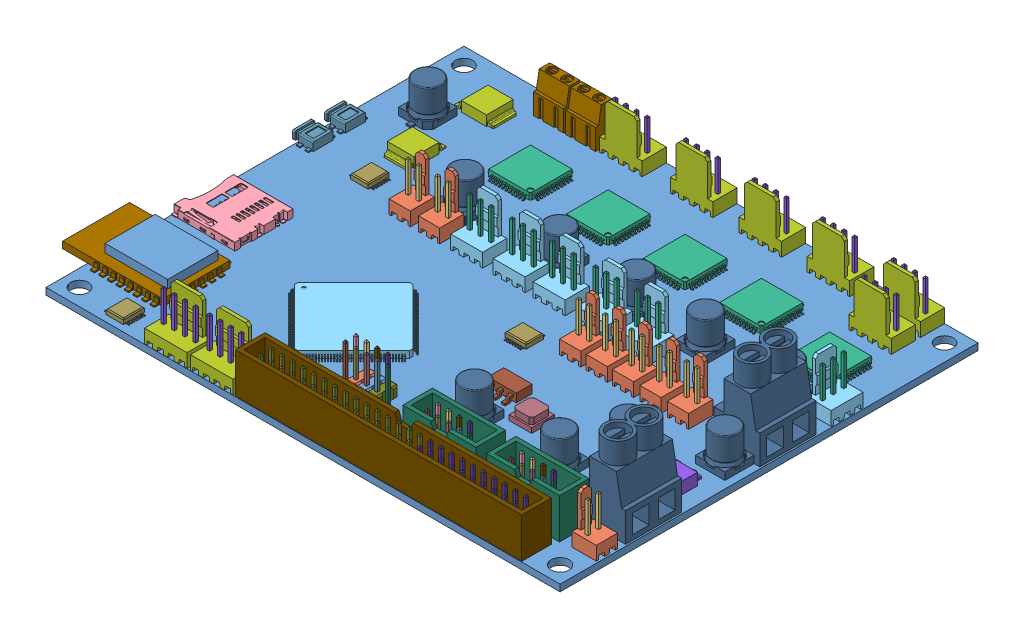
SolidWorks assembly Duet WIfi Rev 4, configuration Predeterminado. Lengths in mm.
Overall size (129 22.52 100).
221 component instances, 40 part files, 0 mates.
Components (placement in the parent):
- Main PCB v56-1: Main PCB v56 [Predeterminado] at origin size (123 1.6 100)
- Molex PCB 2 pin v2-1: Molex PCB 2 pin v2 [Predeterminado] at (-35.5344 13.1082 -6.1109) x (1 0 0) z (0 1 0) size (5.08 5.79 14.92)
  - BASE9710016_1-1: BASE9710016_1 [Predeterminado] at (2.54 2.895 -8.22) size (5.08 5.79 11.5)
  - PINO9710016_1-1: PINO9710016_1 [Predeterminado] at (1.27 3.325 -0.72) size (0.65 0.65 14.2)
  - PINO9710016_1-2: PINO9710016_1 [Predeterminado] at (3.81 3.325 -0.72) size (0.65 0.65 14.2)
- Molex PCB 2 pin v2_1-1: Molex PCB 2 pin v2_1 [Predeterminado] at (-28.4802 13.1082 -6.1109) x (1 0 0) z (0 1 0) size (5.08 5.79 14.92)
  - BASE9710016_1-1: BASE9710016_1 [Predeterminado] at (2.54 2.895 -8.22) size (5.08 5.79 11.5)
  - PINO9710016_1-1: PINO9710016_1 [Predeterminado] at (1.27 3.325 -0.72) size (0.65 0.65 14.2)
  - PINO9710016_1-2: PINO9710016_1 [Predeterminado] at (3.81 3.325 -0.72) size (0.65 0.65 14.2)
- microSD1 v4-1: microSD1 v4 [Predeterminado] at (-62.4462 1.5952 12.9853) x (0 0 1) z (-1 0 0) size (14.1 1.88 15.2)
- Molex PCB 2 pin v2_2-1: Molex PCB 2 pin v2_2 [Predeterminado] at (13.9179 13.1082 2.5426) x (1 0 0) z (0 1 0) size (5.08 5.79 14.92)
  - BASE9710016_1-1: BASE9710016_1 [Predeterminado] at (2.54 2.895 -8.22) size (5.08 5.79 11.5)
  - PINO9710016_1-1: PINO9710016_1 [Predeterminado] at (1.27 3.325 -0.72) size (0.65 0.65 14.2)
  - PINO9710016_1-2: PINO9710016_1 [Predeterminado] at (3.81 3.325 -0.72) size (0.65 0.65 14.2)
- Molex PCB 2 pin v2_3-1: Molex PCB 2 pin v2_3 [Predeterminado] at (20.2886 13.1082 2.5426) x (1 0 0) z (0 1 0) size (5.08 5.79 14.92)
  - BASE9710016_1-1: BASE9710016_1 [Predeterminado] at (2.54 2.895 -8.22) size (5.08 5.79 11.5)
  - PINO9710016_1-1: PINO9710016_1 [Predeterminado] at (1.27 3.325 -0.72) size (0.65 0.65 14.2)
  - PINO9710016_1-2: PINO9710016_1 [Predeterminado] at (3.81 3.325 -0.72) size (0.65 0.65 14.2)
- Molex PCB 2 pin v2_4-1: Molex PCB 2 pin v2_4 [Predeterminado] at (26.5531 13.1082 2.5426) x (1 0 0) z (0 1 0) size (5.08 5.79 14.92)
  - BASE9710016_1-1: BASE9710016_1 [Predeterminado] at (2.54 2.895 -8.22) size (5.08 5.79 11.5)
  - PINO9710016_1-1: PINO9710016_1 [Predeterminado] at (1.27 3.325 -0.72) size (0.65 0.65 14.2)
  - PINO9710016_1-2: PINO9710016_1 [Predeterminado] at (3.81 3.325 -0.72) size (0.65 0.65 14.2)
- Molex PCB 2 pin v2_5-1: Molex PCB 2 pin v2_5 [Predeterminado] at (33.1361 13.1082 2.5426) x (1 0 0) z (0 1 0) size (5.08 5.79 14.92)
  - BASE9710016_1-1: BASE9710016_1 [Predeterminado] at (2.54 2.895 -8.22) size (5.08 5.79 11.5)
  - PINO9710016_1-1: PINO9710016_1 [Predeterminado] at (1.27 3.325 -0.72) size (0.65 0.65 14.2)
  - PINO9710016_1-2: PINO9710016_1 [Predeterminado] at (3.81 3.325 -0.72) size (0.65 0.65 14.2)
- Molex PCB 2 pin v2_6-1: Molex PCB 2 pin v2_6 [Predeterminado] at (39.7191 13.1082 2.5426) x (1 0 0) z (0 1 0) size (5.08 5.79 14.92)
  - BASE9710016_1-1: BASE9710016_1 [Predeterminado] at (2.54 2.895 -8.22) size (5.08 5.79 11.5)
  - PINO9710016_1-1: PINO9710016_1 [Predeterminado] at (1.27 3.325 -0.72) size (0.65 0.65 14.2)
  - PINO9710016_1-2: PINO9710016_1 [Predeterminado] at (3.81 3.325 -0.72) size (0.65 0.65 14.2)
- Molex PCB 3 pin v2 v6-1: Molex PCB 3 pin v2 v6 [Predeterminado] at (-20.7566 13.2093 -6.0914) x (1 0 0) z (0 1 0) size (7.62 5.79 14.92)
  - BASE9710016_2-1: BASE9710016_2 [Predeterminado] at (2.54 2.895 -8.22) size (7.62 5.79 11.5)
  - PINO9710016_2-1: PINO9710016_2 [Predeterminado] at (1.27 3.325 -0.72) size (0.65 0.65 14.2)
  - PINO9710016_2-2: PINO9710016_2 [Predeterminado] at (3.81 3.325 -0.72) size (0.65 0.65 14.2)
  - PINO9710016_2-3: PINO9710016_2 [Predeterminado] at (6.35 3.325 -0.72) size (0.65 0.65 14.2)
- Molex PCB 3 pin v2 v6_1-1: Molex PCB 3 pin v2 v6_1 [Predeterminado] at (-10.5889 13.2093 -6.0914) x (1 0 0) z (0 1 0) size (7.62 5.79 14.92)
  - BASE9710016_2-1: BASE9710016_2 [Predeterminado] at (2.54 2.895 -8.22) size (7.62 5.79 11.5)
  - PINO9710016_2-1: PINO9710016_2 [Predeterminado] at (1.27 3.325 -0.72) size (0.65 0.65 14.2)
  - PINO9710016_2-2: PINO9710016_2 [Predeterminado] at (3.81 3.325 -0.72) size (0.65 0.65 14.2)
  - PINO9710016_2-3: PINO9710016_2 [Predeterminado] at (6.35 3.325 -0.72) size (0.65 0.65 14.2)
- Molex PCB 3 pin v2 v6_2-1: Molex PCB 3 pin v2 v6_2 [Predeterminado] at (-1.0164 13.2093 -6.0914) x (1 0 0) z (0 1 0) size (7.62 5.79 14.92)
  - BASE9710016_2-1: BASE9710016_2 [Predeterminado] at (2.54 2.895 -8.22) size (7.62 5.79 11.5)
  - PINO9710016_2-1: PINO9710016_2 [Predeterminado] at (1.27 3.325 -0.72) size (0.65 0.65 14.2)
  - PINO9710016_2-2: PINO9710016_2 [Predeterminado] at (3.81 3.325 -0.72) size (0.65 0.65 14.2)
  - PINO9710016_2-3: PINO9710016_2 [Predeterminado] at (6.35 3.325 -0.72) size (0.65 0.65 14.2)
- Molex PCB 3 pin v2 v6_3-1: Molex PCB 3 pin v2 v6_3 [Predeterminado] at (9.3326 13.2093 -6.0914) x (1 0 0) z (0 1 0) size (7.62 5.79 14.92)
  - BASE9710016_2-1: BASE9710016_2 [Predeterminado] at (2.54 2.895 -8.22) size (7.62 5.79 11.5)
  - PINO9710016_2-1: PINO9710016_2 [Predeterminado] at (1.27 3.325 -0.72) size (0.65 0.65 14.2)
  - PINO9710016_2-2: PINO9710016_2 [Predeterminado] at (3.81 3.325 -0.72) size (0.65 0.65 14.2)
  - PINO9710016_2-3: PINO9710016_2 [Predeterminado] at (6.35 3.325 -0.72) size (0.65 0.65 14.2)
- Molex PCB 3 pin v2 v6_4-1: Molex PCB 3 pin v2 v6_4 [Predeterminado] at (19.2437 13.2093 -6.0914) x (1 0 0) z (0 1 0) size (7.62 5.79 14.92)
  - BASE9710016_2-1: BASE9710016_2 [Predeterminado] at (2.54 2.895 -8.22) size (7.62 5.79 11.5)
  - PINO9710016_2-1: PINO9710016_2 [Predeterminado] at (1.27 3.325 -0.72) size (0.65 0.65 14.2)
  - PINO9710016_2-2: PINO9710016_2 [Predeterminado] at (3.81 3.325 -0.72) size (0.65 0.65 14.2)
  - PINO9710016_2-3: PINO9710016_2 [Predeterminado] at (6.35 3.325 -0.72) size (0.65 0.65 14.2)
- Molex PCB 4 pin v3-1: Molex PCB 4 pin v3 [Predeterminado] at (-37.9459 13.1477 49.9775) x (1 0 0) z (0 1 0) size (10.16 5.79 14.92)
  - BASE9710016-1: BASE9710016 [Predeterminado] at (2.54 2.895 -8.22) size (10.16 5.79 11.5)
  - PINO9710016-1: PINO9710016 [Predeterminado] at (1.27 3.325 -0.72) size (0.65 0.65 14.2)
  - PINO9710016-2: PINO9710016 [Predeterminado] at (3.81 3.325 -0.72) size (0.65 0.65 14.2)
  - PINO9710016-3: PINO9710016 [Predeterminado] at (6.35 3.325 -0.72) size (0.65 0.65 14.2)
  - PINO9710016-4: PINO9710016 [Predeterminado] at (8.89 3.325 -0.72) size (0.65 0.65 14.2)
- Molex PCB 4 pin v3_1-1: Molex PCB 4 pin v3_1 [Predeterminado] at (-26.9715 13.1477 49.9775) x (1 0 0) z (0 1 0) size (10.16 5.79 14.92)
  - BASE9710016-1: BASE9710016 [Predeterminado] at (2.54 2.895 -8.22) size (10.16 5.79 11.5)
  - PINO9710016-1: PINO9710016 [Predeterminado] at (1.27 3.325 -0.72) size (0.65 0.65 14.2)
  - PINO9710016-2: PINO9710016 [Predeterminado] at (3.81 3.325 -0.72) size (0.65 0.65 14.2)
  - PINO9710016-3: PINO9710016 [Predeterminado] at (6.35 3.325 -0.72) size (0.65 0.65 14.2)
  - PINO9710016-4: PINO9710016 [Predeterminado] at (8.89 3.325 -0.72) size (0.65 0.65 14.2)
- Molex PCB 4 pin v3_2-1: Molex PCB 4 pin v3_2 [Predeterminado] at (-13.0474 13.1477 -49.9787) x (-1 0 0) z (0 1 0) size (10.16 5.79 14.92)
  - BASE9710016-1: BASE9710016 [Predeterminado] at (2.54 2.895 -8.22) size (10.16 5.79 11.5)
  - PINO9710016-1: PINO9710016 [Predeterminado] at (1.27 3.325 -0.72) size (0.65 0.65 14.2)
  - PINO9710016-2: PINO9710016 [Predeterminado] at (3.81 3.325 -0.72) size (0.65 0.65 14.2)
  - PINO9710016-3: PINO9710016 [Predeterminado] at (6.35 3.325 -0.72) size (0.65 0.65 14.2)
  - PINO9710016-4: PINO9710016 [Predeterminado] at (8.89 3.325 -0.72) size (0.65 0.65 14.2)
- Molex PCB 4 pin v3_3-1: Molex PCB 4 pin v3_3 [Predeterminado] at (3.87 13.1477 -49.9787) x (-1 0 0) z (0 1 0) size (10.16 5.79 14.92)
  - BASE9710016-1: BASE9710016 [Predeterminado] at (2.54 2.895 -8.22) size (10.16 5.79 11.5)
  - PINO9710016-1: PINO9710016 [Predeterminado] at (1.27 3.325 -0.72) size (0.65 0.65 14.2)
  - PINO9710016-2: PINO9710016 [Predeterminado] at (3.81 3.325 -0.72) size (0.65 0.65 14.2)
  - PINO9710016-3: PINO9710016 [Predeterminado] at (6.35 3.325 -0.72) size (0.65 0.65 14.2)
  - PINO9710016-4: PINO9710016 [Predeterminado] at (8.89 3.325 -0.72) size (0.65 0.65 14.2)
- Molex PCB 4 pin v3_4-1: Molex PCB 4 pin v3_4 [Predeterminado] at (20.2963 13.1477 -49.9787) x (-1 0 0) z (0 1 0) size (10.16 5.79 14.92)
  - BASE9710016-1: BASE9710016 [Predeterminado] at (2.54 2.895 -8.22) size (10.16 5.79 11.5)
  - PINO9710016-1: PINO9710016 [Predeterminado] at (1.27 3.325 -0.72) size (0.65 0.65 14.2)
  - PINO9710016-2: PINO9710016 [Predeterminado] at (3.81 3.325 -0.72) size (0.65 0.65 14.2)
  - PINO9710016-3: PINO9710016 [Predeterminado] at (6.35 3.325 -0.72) size (0.65 0.65 14.2)
  - PINO9710016-4: PINO9710016 [Predeterminado] at (8.89 3.325 -0.72) size (0.65 0.65 14.2)
- Molex PCB 4 pin v3_5-1: Molex PCB 4 pin v3_5 [Predeterminado] at (36.6134 13.1477 -49.9787) x (-1 0 0) z (0 1 0) size (10.16 5.79 14.92)
  - BASE9710016-1: BASE9710016 [Predeterminado] at (2.54 2.895 -8.22) size (10.16 5.79 11.5)
  - PINO9710016-1: PINO9710016 [Predeterminado] at (1.27 3.325 -0.72) size (0.65 0.65 14.2)
  - PINO9710016-2: PINO9710016 [Predeterminado] at (3.81 3.325 -0.72) size (0.65 0.65 14.2)
  - PINO9710016-3: PINO9710016 [Predeterminado] at (6.35 3.325 -0.72) size (0.65 0.65 14.2)
  - PINO9710016-4: PINO9710016 [Predeterminado] at (8.89 3.325 -0.72) size (0.65 0.65 14.2)
- Molex PCB 4 pin v3_6-1: Molex PCB 4 pin v3_6 [Predeterminado] at (53.5582 13.1477 -49.9787) x (-1 0 0) z (0 1 0) size (10.16 5.79 14.92)
  - BASE9710016-1: BASE9710016 [Predeterminado] at (2.54 2.895 -8.22) size (10.16 5.79 11.5)
  - PINO9710016-1: PINO9710016 [Predeterminado] at (1.27 3.325 -0.72) size (0.65 0.65 14.2)
  - PINO9710016-2: PINO9710016 [Predeterminado] at (3.81 3.325 -0.72) size (0.65 0.65 14.2)
  - PINO9710016-3: PINO9710016 [Predeterminado] at (6.35 3.325 -0.72) size (0.65 0.65 14.2)
  - PINO9710016-4: PINO9710016 [Predeterminado] at (8.89 3.325 -0.72) size (0.65 0.65 14.2)
- Molex PCB 4 pin v3_7-1: Molex PCB 4 pin v3_7 [Predeterminado] at (53.5582 13.1477 -42.9934) x (-1 0 0) z (0 1 0) size (10.16 5.79 14.92)
  - BASE9710016-1: BASE9710016 [Predeterminado] at (2.54 2.895 -8.22) size (10.16 5.79 11.5)
  - PINO9710016-1: PINO9710016 [Predeterminado] at (1.27 3.325 -0.72) size (0.65 0.65 14.2)
  - PINO9710016-2: PINO9710016 [Predeterminado] at (3.81 3.325 -0.72) size (0.65 0.65 14.2)
  - PINO9710016-3: PINO9710016 [Predeterminado] at (6.35 3.325 -0.72) size (0.65 0.65 14.2)
  - PINO9710016-4: PINO9710016 [Predeterminado] at (8.89 3.325 -0.72) size (0.65 0.65 14.2)
- 2 pole terminal block v7-1: 2 pole terminal block v7 [Predeterminado] at (-27.4689 1.6269 -46.8568) x (-1 0 0) z (0 0 -1) size (7.2 9 6)
- 2 pole terminal block v7-2: 2 pole terminal block v7 [Predeterminado] at (-35.1283 1.6572 -46.8568) x (-1 0 0) z (0 0 -1) size (7.2 9 6)
- 2 pole terminal block large v7-1: 2 pole terminal block large v7 [Predeterminado] at (55.6089 1.6 -4.9109) x (0 0 -1) z (1 0 0) size (13.4 19.1 11)
- 2 pole terminal block large v7-2: 2 pole terminal block large v7 [Predeterminado] at (55.6089 1.6 27.2029) x (0 0 -1) z (1 0 0) size (13.4 19.1 11)
- Molex PCB 2 pin v2_7-1: Molex PCB 2 pin v2_7 [Predeterminado] at (61.0807 13.1082 40.8944) x (0 0 -1) z (0 1 0) size (5.08 5.79 14.92)
  - BASE9710016_1-1: BASE9710016_1 [Predeterminado] at (2.54 2.895 -8.22) size (5.08 5.79 11.5)
  - PINO9710016_1-1: PINO9710016_1 [Predeterminado] at (1.27 3.325 -0.72) size (0.65 0.65 14.2)
  - PINO9710016_1-2: PINO9710016_1 [Predeterminado] at (3.81 3.325 -0.72) size (0.65 0.65 14.2)
- Molex PCB 3 pin v2 v6_5-1: Molex PCB 3 pin v2 v6_5 [Predeterminado] at (61.3453 13.2093 -15.0112) x (0 0 -1) z (0 1 0) size (7.62 5.79 14.92)
  - BASE9710016_2-1: BASE9710016_2 [Predeterminado] at (2.54 2.895 -8.22) size (7.62 5.79 11.5)
  - PINO9710016_2-1: PINO9710016_2 [Predeterminado] at (1.27 3.325 -0.72) size (0.65 0.65 14.2)
  - PINO9710016_2-2: PINO9710016_2 [Predeterminado] at (3.81 3.325 -0.72) size (0.65 0.65 14.2)
  - PINO9710016_2-3: PINO9710016_2 [Predeterminado] at (6.35 3.325 -0.72) size (0.65 0.65 14.2)
- Pin Header 2x5 TH Pitch 2.54mm v4-1: Pin Header 2x5 TH Pitch 2.54mm v4 [Predeterminado] at (-5.2178 1.6022 33.3605) x (1 0 0) z (0 1 0) size (10.79 5.08 12.7)
  - Component1_5-1: Component1_5 [Predeterminado] at origin size (0.63 0.63 12.7)
  - Component2-1: Component2 [Predeterminado] at origin size (0.63 0.63 12.7)
  - Component3-1: Component3 [Predeterminado] at origin size (0.63 0.63 12.7)
  - Component4-1: Component4 [Predeterminado] at origin size (0.63 0.63 12.7)
  - Component5-1: Component5 [Predeterminado] at origin size (0.63 0.63 12.7)
  - Component6-1: Component6 [Predeterminado] at origin (suppressed, hidden)
  - Component7-1: Component7 [Predeterminado] at origin (suppressed, hidden)
  - Component8-1: Component8 [Predeterminado] at origin (suppressed, hidden)
  - Component9-1: Component9 [Predeterminado] at origin size (2.54 5.08 2.8)
  - Component10-1: Component10 [Predeterminado] at origin size (0.63 0.63 12.7)
  - Component11-1: Component11 [Predeterminado] at origin size (0.63 0.63 12.7)
  - Component12-1: Component12 [Predeterminado] at origin size (2.54 5.08 2.8)
  - Component13-1: Component13 [Predeterminado] at origin size (2.54 5.08 2.8)
  - Component14-1: Component14 [Predeterminado] at origin size (0.63 0.63 12.7)
  - Component15-1: Component15 [Predeterminado] at origin size (0.63 0.63 12.7)
- Arm cortex Sam4E8E v6 v7-1: Arm cortex Sam4E8E v6 v7 [Predeterminado] at (-17.0062 1.6459 20.877) x (0.707107 0 0.707107) z (-0.707107 0 0.707107) size (22 1.6 22)
  - Component1-1: Component1 [Predeterminado] at origin size (22 1.6 22)
- Trinamic 2660-PA v3-1: Trinamic 2660-PA v3 [Predeterminado] at (-26.4607 1.6002 -30.8647) x (-1 0 -0.000001) z (0.000001 0 -1) size (12 1.6 12)
  - Component1_1-1: Component1_1 [Predeterminado] at origin size (12 1.6 12)
- Trinamic 2660-PA v3-2: Trinamic 2660-PA v3 [Predeterminado] at (-7.8607 1.6002 -30.8647) x (-1 0 -0.000001) z (0.000001 0 -1) size (12 1.6 12)
  - Component1_1-1: Component1_1 [Predeterminado] at origin size (12 1.6 12)
- Trinamic 2660-PA v3-3: Trinamic 2660-PA v3 [Predeterminado] at (10.5393 1.6002 -30.8647) x (-1 0 -0.000001) z (0.000001 0 -1) size (12 1.6 12)
  - Component1_1-1: Component1_1 [Predeterminado] at origin size (12 1.6 12)
- Trinamic 2660-PA v3-4: Trinamic 2660-PA v3 [Predeterminado] at (28.8037 1.6002 -30.8647) x (-1 0 -0.000001) z (0.000001 0 -1) size (12 1.6 12)
  - Component1_1-1: Component1_1 [Predeterminado] at origin size (12 1.6 12)
- Trinamic 2660-PA v3_1-1: Trinamic 2660-PA v3_1 [Predeterminado] at (48.089 1.6002 -27.9115) x (-1 0 -0.000001) z (0.000001 0 -1) size (12 1.6 12)
  - Component1_1-1: Component1_1 [Predeterminado] at origin size (12 1.6 12)
- MOSFET v9-1: MOSFET v9 [Predeterminado] at (-45.1235 1.6199 -39.2021) x (0 0 1) z (-1 0 0) size (6.4 2.4 9.33)
- MOSFET v9-2: MOSFET v9 [Predeterminado] at (-45.3181 1.6199 -21.674) x (-1 0 0) z (0 0 -1) size (6.4 2.4 9.33)
- Power reg v5-1: Power reg v5 [Predeterminado] at (54.1912 1.6402 16.2036) x (-1 0 0) z (0 0 -1) size (6.8 2.8 9.2)
- Duet Wifi daughter board  v25-1: Duet Wifi daughter board  v25 [Predeterminado] at (-55.2292 8.9057 28.17) size (25 1.6 18.4)
  - Component1_2-1: Component1_2 [Predeterminado] at (-0.2708 -7.3057 3.83) size (25 1.6 18.4)
- PCB 7mm cap v8-1: PCB 7mm cap v8 [Predeterminado] at (-5.0295 1.5787 -16.3984) size (7 8 8.14)
  - Component1_3-1: Component1_3 [Predeterminado] at origin size (7 8 8.14)
- PCB 7mm cap v8_1-1: PCB 7mm cap v8_1 [Predeterminado] at (-27.7717 1.5787 -16.5362) size (7 8 8.14)
  - Component1_3-1: Component1_3 [Predeterminado] at origin size (7 8 8.14)
- PCB 7mm cap v8_2-1: PCB 7mm cap v8_2 [Predeterminado] at (13.3988 1.5787 -16.4775) size (7 8 8.14)
  - Component1_3-1: Component1_3 [Predeterminado] at origin size (7 8 8.14)
- PCB 7mm cap v8_3-1: PCB 7mm cap v8_3 [Predeterminado] at (29.911 1.5787 -16.3984) size (7 8 8.14)
  - Component1_3-1: Component1_3 [Predeterminado] at origin size (7 8 8.14)
- PCB 7mm cap v8_4-1: PCB 7mm cap v8_4 [Predeterminado] at (49.8005 1.5787 -16.1299) x (-0.000012 0 -1) z (1 0 -0.000012) size (7 8 8.14)
  - Component1_3-1: Component1_3 [Predeterminado] at origin size (7 8 8.14)
- PCB 7mm cap v8_5-1: PCB 7mm cap v8_5 [Predeterminado] at (42.4342 1.5787 14.6374) x (0 0 1) z (-1 0 0) size (7 8 8.14)
  - Component1_3-1: Component1_3 [Predeterminado] at origin size (7 8 8.14)
- PCB 7mm cap v8_6-1: PCB 7mm cap v8_6 [Predeterminado] at (56.2359 1.5787 5.2974) size (7 8 8.14)
  - Component1_3-1: Component1_3 [Predeterminado] at origin size (7 8 8.14)
- PCB 7mm cap v8_7-1: PCB 7mm cap v8_7 [Predeterminado] at (37.0801 1.5787 25.7026) x (0 0 -1) z (1 0 0) size (7 8 8.14)
  - Component1_3-1: Component1_3 [Predeterminado] at origin size (7 8 8.14)
- PCB 7mm cap v8_8-1: PCB 7mm cap v8_8 [Predeterminado] at (16.7939 1.5787 25.7621) x (-1 0 0) z (0 0 -1) size (7 8 8.14)
  - Component1_3-1: Component1_3 [Predeterminado] at origin size (7 8 8.14)
- PCB 7mm cap v8_9-1: PCB 7mm cap v8_9 [Predeterminado] at (-51.4074 1.5787 -31.2726) x (-1 0 0) z (0 0 -1) size (7 8 8.14)
  - Component1_3-1: Component1_3 [Predeterminado] at origin size (7 8 8.14)
- Power reg R2 v4-1: Power reg R2 v4 [Predeterminado] at (15.3184 1.6131 15.7902) size (6.8 2 7)
- Micro P v5-1: Micro P v5 [Predeterminado] at (6.2858 1.6187 3.3147) size (5 1.2 5.8)
  - Component1_4-1: Component1_4 [Predeterminado] at origin size (5 1.2 5.8)
- Micro P v5-2: Micro P v5 [Predeterminado] at (-46.5775 1.6187 45.9806) x (0 0 -1) z (1 0 0) size (5 1.2 5.8)
  - Component1_4-1: Component1_4 [Predeterminado] at origin size (5 1.2 5.8)
- Micro P v5-3: Micro P v5 [Predeterminado] at (-45.3709 1.6187 -11.358) x (0 0 -1) z (1 0 0) size (5 1.2 5.8)
  - Component1_4-1: Component1_4 [Predeterminado] at origin size (5 1.2 5.8)
- choke v6-1: choke v6 [Predeterminado] at (24.2066 1.6283 19.4931) size (5.4 2.7 5.4)
- button switch v9-1: button switch v9 [Predeterminado] at (-59.392 1.6111 -12.4706) size (5 2 6.4)
- button switch v9-2: button switch v9 [Predeterminado] at (-59.362 1.6111 -20.1424) size (5 2 6.4)
- Pin Header 2x5 TH Pitch 2.54mm v4_1-1: Pin Header 2x5 TH Pitch 2.54mm v4_1 [Predeterminado] at (18.7961 1.6 37.7617) x (1 0 0) z (0 1 0) size (10.79 5.08 12.7)
  - Component1_5-1: Component1_5 [Predeterminado] at origin size (0.63 0.63 12.7)
  - Component2-1: Component2 [Predeterminado] at origin size (0.63 0.63 12.7)
  - Component3-1: Component3 [Predeterminado] at origin size (0.63 0.63 12.7)
  - Component4-1: Component4 [Predeterminado] at origin size (0.63 0.63 12.7)
  - Component5-1: Component5 [Predeterminado] at origin size (0.63 0.63 12.7)
  - Component6-1: Component6 [Predeterminado] at origin (suppressed, hidden)
  - Component7-1: Component7 [Predeterminado] at origin (suppressed, hidden)
  - Component8-1: Component8 [Predeterminado] at origin (suppressed, hidden)
  - Component9-1: Component9 [Predeterminado] at origin size (2.54 5.08 2.8)
  - Component10-1: Component10 [Predeterminado] at origin size (0.63 0.63 12.7)
  - Component11-1: Component11 [Predeterminado] at origin size (0.63 0.63 12.7)
  - Component12-1: Component12 [Predeterminado] at origin size (2.54 5.08 2.8)
  - Component13-1: Component13 [Predeterminado] at origin size (2.54 5.08 2.8)
  - Component14-1: Component14 [Predeterminado] at origin size (0.63 0.63 12.7)
  - Component15-1: Component15 [Predeterminado] at origin size (0.63 0.63 12.7)
- Pin Header 2x5 TH Pitch 2.54mm v4_2-1: Pin Header 2x5 TH Pitch 2.54mm v4_2 [Predeterminado] at (38.8572 1.6 37.7617) x (1 0 0) z (0 1 0) size (10.79 5.08 12.7)
  - Component1_5-1: Component1_5 [Predeterminado] at origin size (0.63 0.63 12.7)
  - Component2-1: Component2 [Predeterminado] at origin size (0.63 0.63 12.7)
  - Component3-1: Component3 [Predeterminado] at origin size (0.63 0.63 12.7)
  - Component4-1: Component4 [Predeterminado] at origin size (0.63 0.63 12.7)
  - Component5-1: Component5 [Predeterminado] at origin size (0.63 0.63 12.7)
  - Component6-1: Component6 [Predeterminado] at origin (suppressed, hidden)
  - Component7-1: Component7 [Predeterminado] at origin (suppressed, hidden)
  - Component8-1: Component8 [Predeterminado] at origin (suppressed, hidden)
  - Component9-1: Component9 [Predeterminado] at origin size (2.54 5.08 2.8)
  - Component10-1: Component10 [Predeterminado] at origin size (0.63 0.63 12.7)
  - Component11-1: Component11 [Predeterminado] at origin size (0.63 0.63 12.7)
  - Component12-1: Component12 [Predeterminado] at origin size (2.54 5.08 2.8)
  - Component13-1: Component13 [Predeterminado] at origin size (2.54 5.08 2.8)
  - Component14-1: Component14 [Predeterminado] at origin size (0.63 0.63 12.7)
  - Component15-1: Component15 [Predeterminado] at origin size (0.63 0.63 12.7)
- 2X5Pin case v6-1: 2X5Pin case v6 [Predeterminado] at (17.4643 1.6 37.7689) x (1 0 0) z (0 1 0) size (17.5 7.08 9.6)
  - Component1_6-1: Component1_6 [Predeterminado] at origin size (17.5 7.08 9.6)
- 2X5Pin case v6_1-1: 2X5Pin case v6_1 [Predeterminado] at (37.4629 1.6 37.7689) x (1 0 0) z (0 1 0) size (17.5 7.08 9.6)
  - Component1_6-1: Component1_6 [Predeterminado] at origin size (17.5 7.08 9.6)
- 25 pin with case v2-1: 25 pin with case v2 [Predeterminado] at (-12.4721 1.5997 44.5087) size (68.5 12.8 7.08)
  - Pin Header 2x15 TH Pitch 2.54mm v2-1: Pin Header 2x15 TH Pitch 2.54mm v2 [Predeterminado] at (0 0.0647 1.8778) x (1 0 0) z (0 1 0) size (38.1 5.08 12.7)
  - Pin Header 2x10 TH Pitch 2.54mm v2-1: Pin Header 2x10 TH Pitch 2.54mm v2 [Predeterminado] at (38.1 0.0647 1.8778) x (1 0 0) z (0 1 0) size (25.4 5.08 12.7)
  - 2X25Pin case v7-1: 2X25Pin case v7 [Predeterminado] x (1 0 0) z (0 1 0) size (68.5 7.08 9.6)
    - Component1_7-1: Component1_7 [Predeterminado] at (-1.5 -1.8778 0.0661) size (68.5 7.08 9.6)
- wifi chip v3-1: wifi chip v3 [Predeterminado] at (-52.469 3.2167 31.4135) x (1 0 0) z (0 1 0) size (15 12 2)
